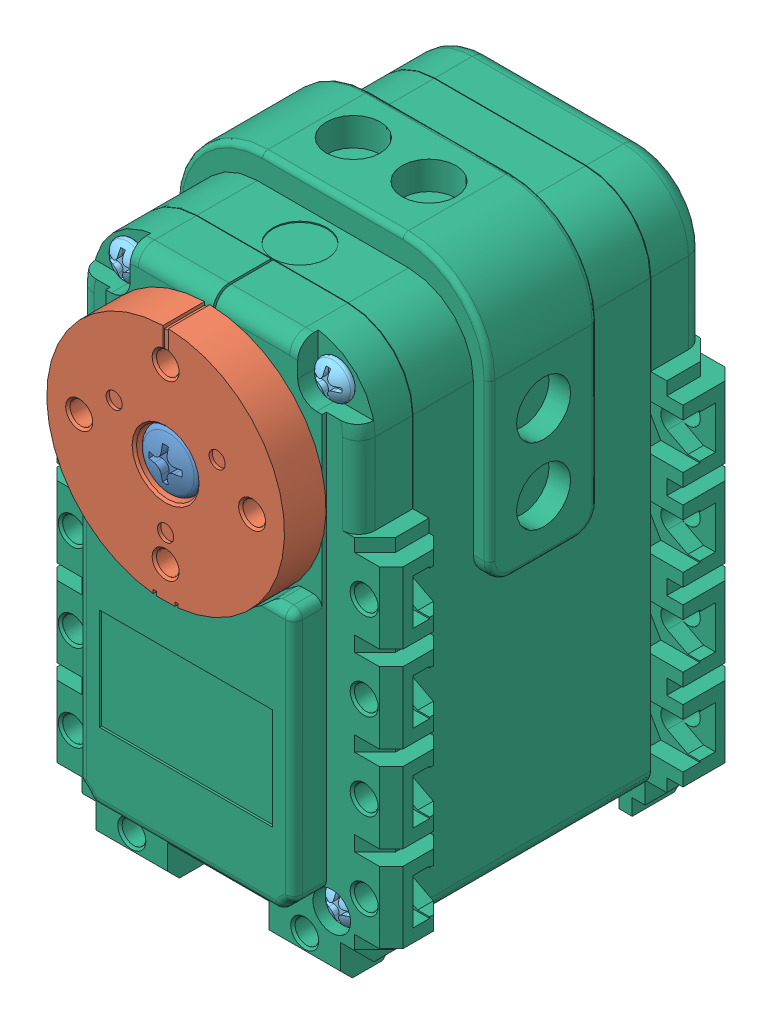
SolidWorks assembly AX-S1, configuration Défaut. Lengths in mm.
Overall size (32 52.5 40.25).
10 component instances, 6 part files, 0 mates.
Components (placement in the parent):
- BHS_M2_6X8-1: BHS_M2_6X8 [Défaut] at (0 0 19.48) x (-1 0 0) z (0 1 0) size (5.5 9.6 5.5)
- DC04_B01_HORN2_DUMMY-1: DC04_B01_HORN2_DUMMY [Défaut] at (0 0 19.03) x (0 1 0) z (0 0 1) size (22 22 6.7)
- DC04_B01_INSERT_M3-1: DC04_B01_INSERT_M3 [Défaut] at (0 0 -18.4) x (-1 0 0) z (0 1 0) size (4.98 7 4.98)
- 099990987____-1: 099990987____ [Défaut] at (5.05 -15.19 -9.75) x (1 0 0) z (0 1 0) size (9.9 9.43 4.9)
- 099990987____-2: 099990987____ [Défaut] at (-4.95 -15.19 -9.75) x (1 0 0) z (0 1 0) size (9.9 9.43 4.9)
- DX124_SCREW-COVER___-1: DX124_SCREW-COVER___ [Défaut] at (9.5 8.5 14.5) x (-1 0 0) z (0 1 0) size (3.5 30.7 3.5)
- DX124_SCREW-COVER___-2: DX124_SCREW-COVER___ [Défaut] at (-9.5 8.5 14.5) x (-1 0 0) z (0 1 0) size (3.5 30.7 3.5)
- DX124_SCREW-COVER___-3: DX124_SCREW-COVER___ [Défaut] at (10.5 -33 14.5) x (-1 0 0) z (0 1 0) size (3.5 30.7 3.5)
- DX124_SCREW-COVER___-4: DX124_SCREW-COVER___ [Défaut] at (-10.5 -33 14.5) x (-1 0 0) z (0 1 0) size (3.5 30.7 3.5)
- ASSY DUMMY-1: ASSY DUMMY [Défaut] at origin size (32 52.5 38.37)
